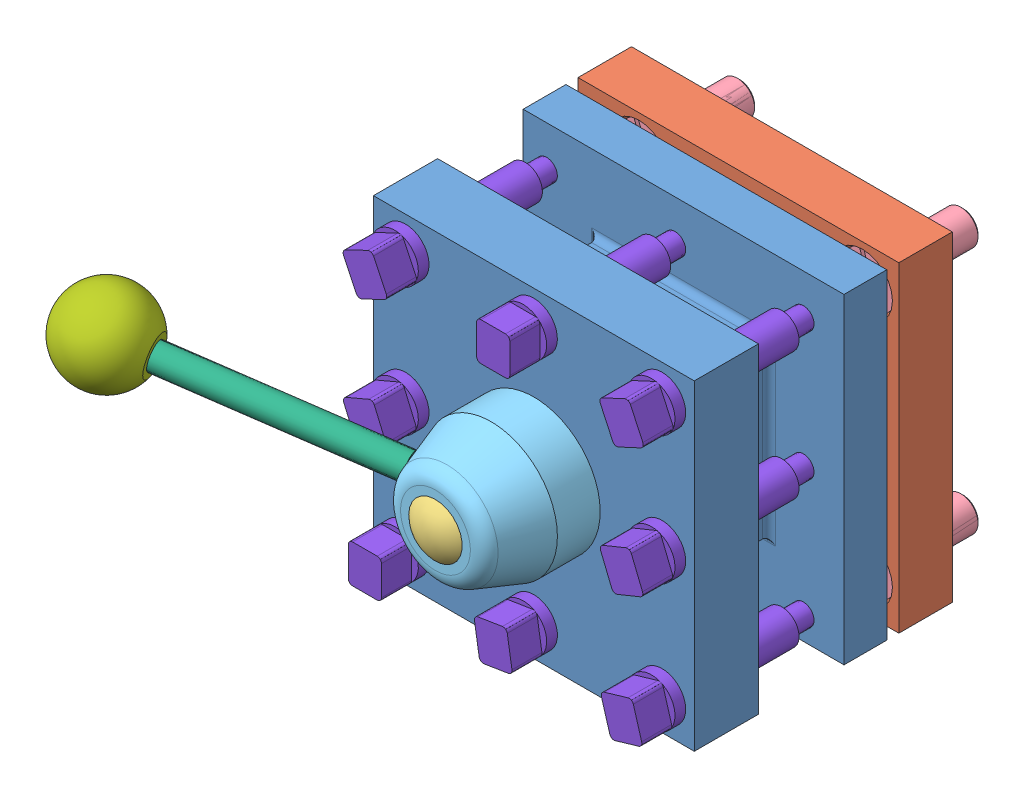
SolidWorks assembly tool assembly 1, configuration Default. Lengths in mm.
Overall size (235.72 150 240.68).
27 component instances, 10 part files, 2 mates.
Components (placement in the parent):
- tool assembly-1: tool assembly [Default] at (-22.3139 -107.9712 -23.1465) size (235.72 150 240.68)
  - tool part1-1: tool part1 [Default] at origin size (150 150 90)
  - tool part2-1: tool part2 [Default] at (0 0 -108.1461) x (1 0 0) z (0 1 0) size (150 34 150)
  - tool part3-1: tool part3 [Default] at (0 0 -34) x (-0.107373 0.994219 0) z (0.994219 0.107373 0) size (27 165 27)
  - tool part6-1: tool part6 [Default] at (58 -58 -98.6461) x (0 -1 0) z (-1 0 0) size (25 44 25)
  - tool part5-1: tool part5 [Default] at (0 0 23) x (-0.181816 -0.983333 0) z (-0.983333 0.181816 0) size (62 46 62)
  - tool part7-1: tool part7 [Default] at (-103.0734 19.058 58.0583) x (-0.281462 -0.902708 -0.325418) z (-0.239374 0.394459 -0.887188) size (12 115 12)
  - tool part4-2: tool part4 [Default] at (-131.6859 24.3484 68.1305) x (0.263126 0.929236 0.259395) z (0.259395 -0.327111 0.908687) size (40 38 40)
  - tool part6-2: tool part6 [Default] at (-58 -58 -98.6461) x (0.158553 -0.987351 0) z (-0.987351 -0.158553 0) size (25 44 25)
  - tool part6-4: tool part6 [Default] at (58 58 -98.6461) x (0.282984 -0.959125 0) z (-0.959125 -0.282984 0) size (25 44 25)
  - tool part6-6: tool part6 [Default] at (-46.453 58 -98.6461) x (0.371154 -0.928571 0) z (-0.928571 -0.371154 0) size (25 44 25)
  - tool part8-2: tool part8 [Default] at (-60 -60 -41.404) x (1 0 0) z (0 -1 0) size (22 85 22)
  - tool part8-3: tool part8 [Default] at (0 -60 -41.404) x (0.987351 0.158553 0) z (0.158553 -0.987351 0) size (22 85 22)
  - tool part8-5: tool part8 [Default] at (60 -60 -41.404) x (0.959125 0.282984 0) z (0.282984 -0.959125 0) size (22 85 22)
  - tool part8-7: tool part8 [Default] at (60 0 -41.404) x (-0.926095 -0.377289 0) z (-0.377289 0.926095 0) size (22 85 22)
  - tool part8-9: tool part8 [Default] at (60 60 -41.404) x (0.906989 0.421154 0) z (0.421154 -0.906989 0) size (22 85 22)
  - tool part8-11: tool part8 [Default] at (-60 60 -41.404) x (0.902849 0.429957 0) z (0.429957 -0.902849 0) size (22 85 22)
  - tool part8-13: tool part8 [Default] at (-60 0 -41.404) x (0.919615 0.39282 0) z (0.39282 -0.919615 0) size (22 85 22)
  - tool part910-4: tool part910 [Default] at (0 -60 -90.0043) x (0.322217 -0.946666 0) z (-0.946666 -0.322217 0) size (10.13 17.09 10.14)
  - tool part910-5: tool part910 [Default] at (-60 0 -90.0043) x (-0.946666 -0.322217 0) z (-0.322217 0.946666 0) size (10.13 17.09 10.14)
  - tool part910-6: tool part910 [Default] at (0 60 -90.0043) x (-0.322217 0.946666 0) z (0.946666 0.322217 0) size (10.13 17.09 10.14)
  - tool part910-7: tool part910 [Default] at (60 0 -90.0043) x (0.946666 0.322217 0) z (0.322217 -0.946666 0) size (10.13 17.09 10.14)
  - tool part9-1: tool part9 [Default] at (0 60 -93.575) size (10 10 10)
  - tool part9-2: tool part9 [Default] at (-60 0 -93.575) x (0 1 0) z (0 0 1) size (10 10 10)
  - tool part9-3: tool part9 [Default] at (0 -60 -93.575) x (-1 0 0) z (0 0 1) size (10 10 10)
  - tool part9-4: tool part9 [Default] at (60 0 -93.575) x (0 -1 0) z (0 0 1) size (10 10 10)
- tool part8-1: tool part8 [Default] at (-22.3139 -47.9712 -64.5506) x (1 0 0) z (0 -1 0) size (22 85 22)
Mates (geometry in assembly coordinates):
- Concentric1: concentric: cylinder of tool assembly-1/tool part1-1 through (-22.3139 -47.9712 -23.1465) axis (0 0 1) radius 7; cylinder of tool part8-1 through (-22.3139 -47.9712 -89.1465) axis (0 0 -1) radius 8
- Coincident3: coincident anti-aligned: plane of tool assembly-1/tool part1-1 through (-22.3139 -107.9712 -23.1465) normal (0 0 1); plane of tool part8-1 through (-14.3139 -47.9712 -23.1465) normal (0 0 -1)
